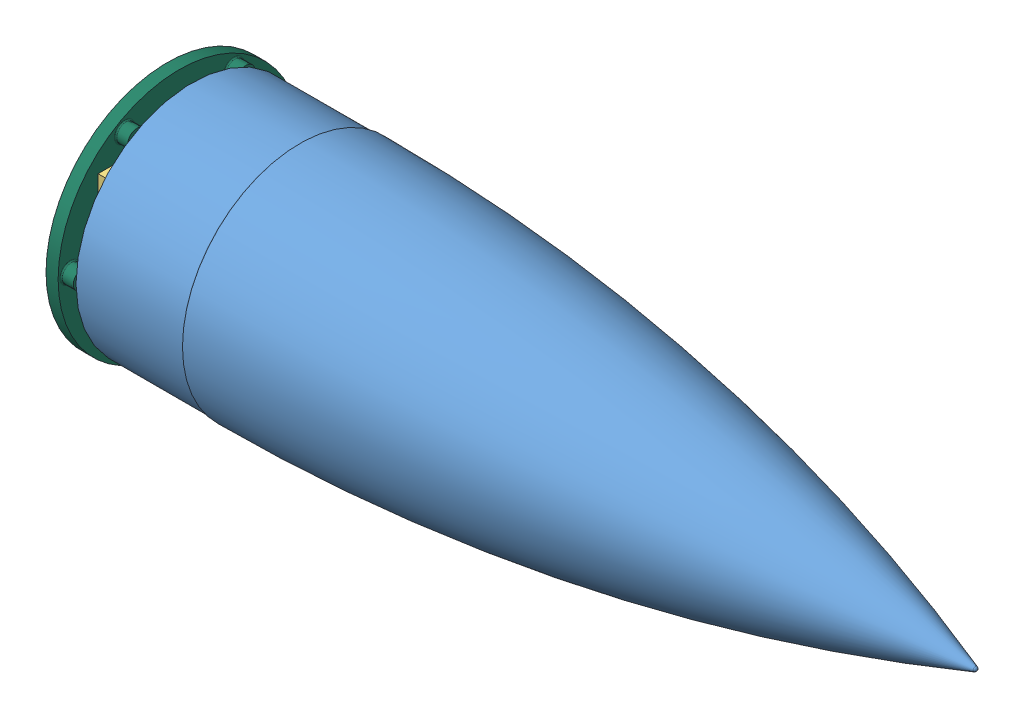
SolidWorks assembly nose_asm, configuration 預設. Lengths in mm.
Overall size (708.47 200 200).
227 component instances, 67 part files, 3 mates.
Components (placement in the parent):
- nosecone-1: nosecone [預設] at origin size (647.8 194 194)
- avionics_asm-1: avionics_asm [預設] at (-668.4373 0 0) size (460.03 200 200)
  - avionics_base_1-1: avionics_base_1 [預設] at (85 0 0) size (10 165 165)
  - avionics_reassemb-2: avionics_reassemb [Default] at (153.5 -32.5546 1.2351) x (1 0 0) z (0 -1 0) size (134.36 127 95)
    - PCB_board_box_reassemb-1: PCB_board_box_reassemb [Default] at (0 -1.2351 -1.0546) size (121.33 127 95)
      - PCB_board_box_buttom-1: PCB_board_box_buttom [Default] at origin size (115 105 1)
      - PCB_board_box_front-1: PCB_board_box_front [Default] at (0 53.5 -36.5) x (0 0 -1) z (0 -1 0) size (75 115 1)
      - PCB_board_box_back-1: PCB_board_box_back [Default] at (0 -53.5 -36.5) x (0 0 1) z (0 1 0) size (75 115 1)
      - PCB_board_box_right-1: PCB_board_box_right [Default] at (58.5 0 -36.5) x (0 0 1) z (-1 0 0) size (85 127 1)
      - PCB_board_box_top-1: PCB_board_box_top [Default] at (0 0 -74) x (0 -1 0) z (0 0 1) size (105 115 1)
      - PCB_board_box_left-1: PCB_board_box_left [Default] at (-57.5 0 -36.5) x (0 0 1) z (-1 0 0) size (85 127 1)
      - connector_1-1: connector_1 [Default] at (-32.5 49.6 2.1) x (1 0 0) z (0 0 -1) size (10 10 10)
      - connector_1-2: connector_1 [Default] at (57.5 58.5 -36.5) x (0 0 1) z (-1 0 0) size (10 10 10)
      - connector_1-3: connector_1 [Default] at (57.5 -58.5 -36.5) x (0 0 -1) z (-1 0 0) size (10 10 10)
      - connector_1-4: connector_1 [Default] at (32.5 -49.6 2.1) x (-1 0 0) z (0 0 -1) size (10 10 10)
      - connector_1-5: connector_1 [Default] at (-32.5 -49.6 2.1) x (-1 0 0) z (0 0 -1) size (10 10 10)
      - connector_1-6: connector_1 [Default] at (-57.5 48.5 6) x (0 1 0) z (1 0 0) size (10 10 10)
      - connector_1-7: connector_1 [Default] at (-57.5 -48.5 6) x (0 1 0) z (1 0 0) size (10 10 10)
      - connector_1-8: connector_1 [Default] at (-57.5 58.5 -56.5) x (0 0 -1) z (1 0 0) size (10 10 10)
      - connector_1-9: connector_1 [Default] at (-57.5 -58.5 -56.5) x (0 0 1) z (1 0 0) size (10 10 10)
      - connector_1-10: connector_1 [Default] at (52.5 0 -74) x (0 -1 0) z (0 0 -1) size (10 10 10)
      - connector_1-11: connector_1 [Default] at (52.5 -49.6 -75.1) size (10 10 10)
      - connector_1-12: connector_1 [Default] at (-52.5 -54.6 -70.1) x (-1 0 0) z (0 1 0) size (10 10 10)
      - connector_1-13: connector_1 [Default] at (-52.5 49.6 -75.1) x (-1 0 0) z (0 0 1) size (10 10 10)
      - connector_1-14: connector_1 [Default] at (32.5 49.6 2.1) x (1 0 0) z (0 0 -1) size (10 10 10)
      - connector_1-15: connector_1 [Default] at (52.5 49.6 -75.1) x (-1 0 0) z (0 0 1) size (10 10 10)
      - ISO 10642 - M3 x  8-1: ISO 10642 - M3 x  8 [Default] at (-52.5 48.6 -71.3293) x (0 0 -1) z (-1 0 0) size (8 6 6)
      - ISO 10642 - M3 x  8-2: ISO 10642 - M3 x  8 [Default] at (-52.5 50.8293 -69.1) x (0 1 0) z (-1 0 0) size (8 6 6)
      - ISO 10642 - M3 x  8-3: ISO 10642 - M3 x  8 [Default] at (-52.5 -48.6 -71.3293) x (0 0 -1) z (-1 0 0) size (8 6 6)
      - ISO 10642 - M3 x  8-4: ISO 10642 - M3 x  8 [Default] at (-52.5 -50.8293 -69.1) x (0 -1 0) z (-1 0 0) size (8 6 6)
      - ISO 10642 - M3 x  8-5: ISO 10642 - M3 x  8 [Default] at (52.5 -50.7586 -69.1) x (0 -1 0) z (-1 0 0) size (8 6 6)
      - ISO 10642 - M3 x  8-6: ISO 10642 - M3 x  8 [Default] at (52.5 -48.6 -71.2586) x (0 0 -1) z (-1 0 0) size (8 6 6)
      - ISO 10642 - M3 x  8-7: ISO 10642 - M3 x  8 [Default] at (32.5 -48.6 -1.7414) x (0 0 1) z (-1 0 0) size (8 6 6)
      - ISO 10642 - M3 x  8-8: ISO 10642 - M3 x  8 [Default] at (32.5 -50.7586 -3.9) x (0 -1 0) z (-1 0 0) size (8 6 6)
      - ISO 10642 - M3 x  8-9: ISO 10642 - M3 x  8 [Default] at (-32.5 -48.6 -1.7414) x (0 0 1) z (-1 0 0) size (8 6 6)
      - ISO 10642 - M3 x  8-10: ISO 10642 - M3 x  8 [Default] at (-32.5 -50.7586 -3.9) x (0 -1 0) z (-1 0 0) size (8 6 6)
      - ISO 10642 - M3 x  8-11: ISO 10642 - M3 x  8 [Default] at (32.5 48.6 -1.7414) x (0 0 1) z (-1 0 0) size (8 6 6)
      - ISO 10642 - M3 x  8-12: ISO 10642 - M3 x  8 [Default] at (32.5 50.7586 -3.9) x (0 1 0) z (-1 0 0) size (8 6 6)
      - ISO 10642 - M3 x  8-13: ISO 10642 - M3 x  8 [Default] at (-32.5 48.6 -1.6707) x (0 0 1) z (-1 0 0) size (8 6 6)
      - ISO 10642 - M3 x  8-14: ISO 10642 - M3 x  8 [Default] at (-32.5 50.7586 -3.9) x (0 1 0) z (-1 0 0) size (8 6 6)
      - ISO 10642 - M3 x  8-15: ISO 10642 - M3 x  8 [Default] at (52.5 48.6 -71.2586) x (0 0 -1) z (-1 0 0) size (8 6 6)
      - ISO 10642 - M3 x  8-16: ISO 10642 - M3 x  8 [Default] at (52.5 50.7586 -69.1) x (0 1 0) z (-1 0 0) size (8 6 6)
      - ISO 10642 - M3 x  8-17: ISO 10642 - M3 x  8 [Default] at (51.5 0 -76.7414) x (0 0 1) z (-1 0 0) size (8 6 6)
      - ISO 10642 - M3 x  8-18: ISO 10642 - M3 x  8 [Default] at (54.7586 0 -80) x (1 0 0) z (0 0 -1) size (8 6 6)
      - ISO 10642 - M3 x  8-19: ISO 10642 - M3 x  8 [Default] at (54.7586 -59.5 -36.5) x (1 0 0) z (0 0 -1) size (8 6 6)
      - ISO 10642 - M3 x  8-20: ISO 10642 - M3 x  8 [Default] at (51.5 -56.2414 -36.5) x (0 1 0) z (-1 0 0) size (8 6 6)
      - ISO 10642 - M3 x  8-21: ISO 10642 - M3 x  8 [Default] at (51.5 56.2414 -36.5) x (0 -1 0) z (-1 0 0) size (8 6 6)
      - ISO 10642 - M3 x  8-22: ISO 10642 - M3 x  8 [Default] at (54.8293 59.5 -36.5) x (1 0 0) z (0 0 -1) size (8 6 6)
      - ISO 10642 - M3 x  8-23: ISO 10642 - M3 x  8 [Default] at (-51.5 56.1707 -56.5) x (0 -1 0) z (-1 0 0) size (8 6 6)
      - ISO 10642 - M3 x  8-25: ISO 10642 - M3 x  8 [Default] at (-51.5 48.5 3.7414) x (0 0 -1) z (-1 0 0) size (8 6 6)
      - ISO 10642 - M3 x  8-28: ISO 10642 - M3 x  8 [Default] at (-51.5 -48.5 3.7414) x (0 0 -1) z (-1 0 0) size (8 6 6)
      - ISO 10642 - M3 x  8-30: ISO 10642 - M3 x  8 [Default] at (-51.5 -56.1707 -56.5) x (0 1 0) z (-1 0 0) size (8 6 6)
      - ISO 4032 - M3-1: ISO 4032 - M3 [Default] at (-52.5 48.6 -77.5) x (0 0 1) z (-1 0 0) size (2.4 6.35 5.5)
      - ISO 4032 - M3-2: ISO 4032 - M3 [Default] at (-52.5 54.6 -69.1) x (0 1 0) z (-1 0 0) size (2.4 6.35 5.5)
      - ISO 4032 - M3-3: ISO 4032 - M3 [Default] at (-51.5 52.5 -56.5) x (0 -1 0) z (-1 0 0) size (2.4 6.35 5.5)
      - ISO 4032 - M3-4: ISO 4032 - M3 [Default] at (-52.5 -48.6 -75.1) x (0 0 -1) z (-1 0 0) size (2.4 6.35 5.5)
      - ISO 4032 - M3-5: ISO 4032 - M3 [Default] at (-52.5 -54.6 -69.1) x (0 -1 0) z (-1 0 0) size (2.4 6.35 5.5)
      - ISO 4032 - M3-6: ISO 4032 - M3 [Default] at (-51.5 -52.5 -56.5) x (0 1 0) z (-1 0 0) size (2.4 6.35 5.5)
      - ISO 4032 - M3-7: ISO 4032 - M3 [Default] at (-51.5 -48.5 0) x (0 0 -1) z (-1 0 0) size (2.4 6.35 5.5)
      - ISO 4032 - M3-8: ISO 4032 - M3 [Default] at (-51.5 48.5 0) x (0 0 -1) z (-1 0 0) size (2.4 6.35 5.5)
      - ISO 4032 - M3-9: ISO 4032 - M3 [Default] at (-32.5 57 -3.9) x (0 -1 0) z (-1 0 0) size (2.4 6.35 5.5)
      - ISO 4032 - M3-10: ISO 4032 - M3 [Default] at (-32.5 48.6 4.5) x (0 0 -1) z (-1 0 0) size (2.4 6.35 5.5)
      - ISO 4032 - M3-11: ISO 4032 - M3 [Default] at (-32.5 -48.6 2.1) x (0 0 1) z (-1 0 0) size (2.4 6.35 5.5)
      - ISO 4032 - M3-12: ISO 4032 - M3 [Default] at (-32.5 -57 -3.9) x (0 1 0) z (-1 0 0) size (2.4 6.35 5.5)
      - ISO 4032 - M3-13: ISO 4032 - M3 [Default] at (52.5 -48.6 -75.1) x (0 0 -1) z (-1 0 0) size (2.4 6.35 5.5)
      - ISO 4032 - M3-14: ISO 4032 - M3 [Default] at (52.5 -54.6 -69.1) x (0 -1 0) z (-1 0 0) size (2.4 6.35 5.5)
      - ISO 4032 - M3-15: ISO 4032 - M3 [Default] at (52.5 48.6 -75.1) x (0 0 -1) z (-1 0 0) size (2.4 6.35 5.5)
      - ISO 4032 - M3-16: ISO 4032 - M3 [Default] at (52.5 54.6 -69.1) x (0 1 0) z (-1 0 0) size (2.4 6.35 5.5)
      - ISO 4032 - M3-17: ISO 4032 - M3 [Default] at (32.5 57 -3.9) x (0 -1 0) z (-1 0 0) size (2.4 6.35 5.5)
      - ISO 4032 - M3-18: ISO 4032 - M3 [Default] at (32.5 48.6 4.5) x (0 0 -1) z (-1 0 0) size (2.4 6.35 5.5)
      - ISO 4032 - M3-19: ISO 4032 - M3 [Default] at (32.5 -48.6 4.5) x (0 0 -1) z (-1 0 0) size (2.4 6.35 5.5)
      - ISO 4032 - M3-20: ISO 4032 - M3 [Default] at (32.5 -57 -3.9) x (0 1 0) z (-1 0 0) size (2.4 6.35 5.5)
      - ISO 4032 - M3-21: ISO 4032 - M3 [Default] at (51.5 -52.5 -36.5) x (0 1 0) z (-1 0 0) size (2.4 6.35 5.5)
      - ISO 4032 - M3-22: ISO 4032 - M3 [Default] at (51.5 52.5 -36.5) x (0 -1 0) z (-1 0 0) size (2.4 6.35 5.5)
      - ISO 4032 - M3-23: ISO 4032 - M3 [Default] at (58.5 0 -80) size (2.4 6.35 5.5)
      - ISO 4032 - M3-24: ISO 4032 - M3 [Default] at (58.5 -59.5 -36.5) size (2.4 6.35 5.5)
      - ISO 4032 - M3-25: ISO 4032 - M3 [Default] at (58.5 59.5 -36.5) size (2.4 6.35 5.5)
    - PCB-1: PCB [Default] at (47.58 -45.05 -4.8556) x (0 1 0) z (0 0 -1) size (90.17 95.89 17.8)
    - copper_pillar_M3_L15-1: copper_pillar_M3_L15 [Default] at (42.5 -36.16 0) x (1 0 0) z (0 1 0) size (5.77 16 5)
    - copper_pillar_M3_L15-2: copper_pillar_M3_L15 [Default] at (-43.225 40.04 0) x (1 0 0) z (0 1 0) size (5.77 16 5)
    - copper_pillar_M3_L15-3: copper_pillar_M3_L15 [Default] at (42.5 37.5 0) x (1 0 0) z (0 1 0) size (5.77 16 5)
    - copper_pillar_M3_L15-4: copper_pillar_M3_L15 [Default] at (-43.225 -39.97 0) x (1 0 0) z (0 1 0) size (5.77 16 5)
    - washerM3x0.5h-1: washerM3x0.5h [Default] at (-43.225 -39.97 -4.5) size (6.7 6.7 0.5)
    - washerM3x0.5h-2: washerM3x0.5h [Default] at (42.5 -36.16 -4.5) size (6.7 6.7 0.5)
    - washerM3x0.5h-3: washerM3x0.5h [Default] at (-43.225 40.04 -4) x (1 0 0) z (0 0 -1) size (6.7 6.7 0.5)
    - washerM3x0.5h-4: washerM3x0.5h [Default] at (42.5 37.5 -4) x (1 0 0) z (0 0 -1) size (6.7 6.7 0.5)
    - copper_pillar_M3_L15_1-1: copper_pillar_M3_L15_1 [Default] at (42.5 -36.16 -5.3556) x (1 0 0) z (0 1 0) size (5.77 26 5)
    - copper_pillar_M3_L15_1-2: copper_pillar_M3_L15_1 [Default] at (42.5 37.5 -5.3556) x (1 0 0) z (0 1 0) size (5.77 26 5)
    - copper_pillar_M3_L15_1-3: copper_pillar_M3_L15_1 [Default] at (-43.225 40.04 -5.3556) x (1 0 0) z (0 1 0) size (5.77 26 5)
    - copper_pillar_M3_L15_1-4: copper_pillar_M3_L15_1 [Default] at (-43.225 -39.97 -5.3556) x (1 0 0) z (0 1 0) size (5.77 26 5)
    - washerM3x0.5h-5: washerM3x0.5h [Default] at (-43.225 40.04 -5.3556) size (6.7 6.7 0.5)
    - washerM3x0.5h-6: washerM3x0.5h [Default] at (-43.225 -39.97 -4.8556) x (1 0 0) z (0 0 -1) size (6.7 6.7 0.5)
    - washerM3x0.5h-7: washerM3x0.5h [Default] at (42.5 -36.16 -4.8556) x (1 0 0) z (0 0 -1) size (6.7 6.7 0.5)
    - washerM3x0.5h-8: washerM3x0.5h [Default] at (42.5 37.5 -4.8556) x (1 0 0) z (0 0 -1) size (6.7 6.7 0.5)
    - washerM3x0.5h-9: washerM3x0.5h [Default] at (-43.225 40.04 -19.3556) x (1 0 0) z (0 0 -1) size (6.7 6.7 0.5)
    - washerM3x0.5h-10: washerM3x0.5h [Default] at (-43.225 -39.97 -19.3556) x (1 0 0) z (0 0 -1) size (6.7 6.7 0.5)
    - washerM3x0.5h-11: washerM3x0.5h [Default] at (42.5 -36.16 -19.3556) x (1 0 0) z (0 0 -1) size (6.7 6.7 0.5)
    - washerM3x0.5h-12: washerM3x0.5h [Default] at (42.5 37.5 -19.3556) x (1 0 0) z (0 0 -1) size (6.7 6.7 0.5)
    - STM32 Communication Board ver1.0-1: STM32 Communication Board ver1.0 [Default] at (42.5 -36.16 -21.3601) x (0 1 0) z (0 0 -1) size (90.17 95.89 10)
    - washerM3x0.5h-13: washerM3x0.5h [Default] at (42.5 -36.16 -21.3601) x (1 0 0) z (0 0 -1) size (6.7 6.7 0.5)
    - washerM3x0.5h-14: washerM3x0.5h [Default] at (-43.225 -39.97 -21.3601) x (1 0 0) z (0 0 -1) size (6.7 6.7 0.5)
    - washerM3x0.5h-15: washerM3x0.5h [Default] at (42.5 37.5 -21.3601) x (1 0 0) z (0 0 -1) size (6.7 6.7 0.5)
    - washerM3x0.5h-16: washerM3x0.5h [Default] at (-43.225 40.04 -21.3601) x (1 0 0) z (0 0 -1) size (6.7 6.7 0.5)
    - copper_pillar_M3_L25_1-1: copper_pillar_M3_L25_1 [Default] at (-43.225 -39.97 -21.8601) x (1 0 0) z (0 1 0) size (5.77 37 5)
    - copper_pillar_M3_L25_1-2: copper_pillar_M3_L25_1 [Default] at (42.5 -36.16 -21.8601) x (1 0 0) z (0 1 0) size (5.77 37 5)
    - copper_pillar_M3_L25_1-3: copper_pillar_M3_L25_1 [Default] at (42.5 37.5 -21.8601) x (1 0 0) z (0 1 0) size (5.77 37 5)
    - copper_pillar_M3_L25_1-4: copper_pillar_M3_L25_1 [Default] at (-43.225 40.04 -21.8601) x (1 0 0) z (0 1 0) size (5.77 37 5)
    - washerM3x0.5h-17: washerM3x0.5h [Default] at (42.5 37.5 -47.3601) size (6.7 6.7 0.5)
    - washerM3x0.5h-18: washerM3x0.5h [Default] at (-43.225 40.04 -46.8601) x (1 0 0) z (0 0 -1) size (6.7 6.7 0.5)
    - washerM3x0.5h-19: washerM3x0.5h [Default] at (42.5 -36.16 -47.3601) size (6.7 6.7 0.5)
    - washerM3x0.5h-20: washerM3x0.5h [Default] at (-43.225 -39.97 -47.3601) size (6.7 6.7 0.5)
    - empty_board-1: empty_board [Default] at (0.08 0.12 -47.3601) x (0 1 0) z (-1 0 0) size (90 1.45 95)
    - MTi-1_v3-1: MTi-1_v3 [Default] at (-8.5645 -18.7527 -51.9664) x (0 1 0) z (0 0 -1) size (53.34 66.07 22.31)
      - Board_1v2(2)^MTi-1-SoB_v2-1: Board_1v2(2)^MTi-1-SoB_v2 [Default] at origin size (12.15 12.15 1.56)
        - Open CASCADE STEP translator 6.8 2.1.1^Board_1v2(2)_MTi-1-SoB_v2-1: Open CASCADE STEP translator 6.8 2.1.1^Board_1v2(2)_MTi-1-SoB_v2 [Default] at (0 0 -1.5563) size (12.15 12.15 1.56)
          - Open CASCADE STEP translator 6.8 2.1.1.1^Open CASCADE STEP translator_ 6.8 2.1.1_Board_1v2(2)_MTi-1-SoB_v2-1: Open CASCADE STEP translator 6.8 2.1.1.1^Open CASCADE STEP translator_ 6.8 2.1.1_Board_1v2(2)_MTi-1-SoB_v2 [Default] at origin size (12.15 12.15 1.56)
      - U200_1v2(2)^MTi-1-SoB_v2-1: U200_1v2(2)^MTi-1-SoB_v2 [Default] at origin size (3.1 3.3 0.6)
        - 7460079024(2)^U200_1v2(2)_MTi-1-SoB_v2-1: 7460079024(2)^U200_1v2(2)_MTi-1-SoB_v2 [Default] at (5.6 3.4 0) size (3.1 3.3 0.6)
          - Extruded(2)^7460079024(2)_U200_1v2(2)_MTi-1-SoB_v2-1: Extruded(2)^7460079024(2)_U200_1v2(2)_MTi-1-SoB_v2 [Default] at origin size (3.1 3.3 0.6)
      - C200_1v2(2)^MTi-1-SoB_v2-1: C200_1v2(2)^MTi-1-SoB_v2 [Default] at origin size (1.05 0.55 0.55)
        - Cap_0402(2)^C200_1v2(2)_MTi-1-SoB_v2-1: Cap_0402(2)^C200_1v2(2)_MTi-1-SoB_v2 [Default] at (5.3999 6.9749 0.26) x (-1 0 0) z (0 0 1) size (1.05 0.55 0.55)
      - C201_1v2(2)^MTi-1-SoB_v2-1: C201_1v2(2)^MTi-1-SoB_v2 [Default] at origin size (1.05 0.55 0.55)
        - Cap_0402(2)^C201_1v2(2)_MTi-1-SoB_v2-1: Cap_0402(2)^C201_1v2(2)_MTi-1-SoB_v2 [Default] at (6.7999 1.375 0.26) x (-1 0 0) z (0 0 1) size (1.05 0.55 0.55)
      - C204_1v2(2)^MTi-1-SoB_v2-1: C204_1v2(2)^MTi-1-SoB_v2 [Default] at origin size (1.05 0.55 0.55)
        - Cap_0402(2)^C204_1v2(2)_MTi-1-SoB_v2-1: Cap_0402(2)^C204_1v2(2)_MTi-1-SoB_v2 [Default] at (8.1999 3.0749 0.26) x (-1 0 0) z (0 0 1) size (1.05 0.55 0.55)
      - C205_1v2(2)^MTi-1-SoB_v2-1: C205_1v2(2)^MTi-1-SoB_v2 [Default] at origin size (1.05 0.55 0.55)
        - Cap_0402(2)^C205_1v2(2)_MTi-1-SoB_v2-1: Cap_0402(2)^C205_1v2(2)_MTi-1-SoB_v2 [Default] at (4.2001 0.8251 0.26) x (1 0 0) z (0 0 1) size (1.05 0.55 0.55)
      - C206_1v2(2)^MTi-1-SoB_v2-1: C206_1v2(2)^MTi-1-SoB_v2 [Default] at origin size (0.55 1.05 0.55)
        - Cap_0402(2)^C206_1v2(2)_MTi-1-SoB_v2-1: Cap_0402(2)^C206_1v2(2)_MTi-1-SoB_v2 [Default] at (3.1251 4.5999 0.26) x (0 -1 0) z (0 0 1) size (1.05 0.55 0.55)
      - C207_1v2(2)^MTi-1-SoB_v2-1: C207_1v2(2)^MTi-1-SoB_v2 [Default] at origin size (1.05 0.55 0.55)
        - Cap_0402(2)^C207_1v2(2)_MTi-1-SoB_v2-1: Cap_0402(2)^C207_1v2(2)_MTi-1-SoB_v2 [Default] at (7.3001 5.4251 0.26) x (1 0 0) z (0 0 1) size (1.05 0.55 0.55)
      - C208_1v2(2)^MTi-1-SoB_v2-1: C208_1v2(2)^MTi-1-SoB_v2 [Default] at origin size (0.55 1.05 0.55)
        - Cap_0402(2)^C208_1v2(2)_MTi-1-SoB_v2-1: Cap_0402(2)^C208_1v2(2)_MTi-1-SoB_v2 [Default] at (3.1251 2.5999 0.26) x (0 -1 0) z (0 0 1) size (1.05 0.55 0.55)
      - C209_1v2(2)^MTi-1-SoB_v2-1: C209_1v2(2)^MTi-1-SoB_v2 [Default] at origin size (1.05 0.55 0.55)
        - Cap_0402(2)^C209_1v2(2)_MTi-1-SoB_v2-1: Cap_0402(2)^C209_1v2(2)_MTi-1-SoB_v2 [Default] at (8.6001 1.4251 0.26) x (1 0 0) z (0 0 1) size (1.05 0.55 0.55)
      - C300_1v2(2)^MTi-1-SoB_v2-1: C300_1v2(2)^MTi-1-SoB_v2 [Default] at origin size (0.55 1.05 0.55)
        - Cap_0402(2)^C300_1v2(2)_MTi-1-SoB_v2-1: Cap_0402(2)^C300_1v2(2)_MTi-1-SoB_v2 [Default] at (10.425 8.2999 0.26) x (0 -1 0) z (0 0 1) size (1.05 0.55 0.55)
      - C301_1v2(2)^MTi-1-SoB_v2-1: C301_1v2(2)^MTi-1-SoB_v2 [Default] at origin size (1.05 0.55 0.55)
        - Cap_0402(2)^C301_1v2(2)_MTi-1-SoB_v2-1: Cap_0402(2)^C301_1v2(2)_MTi-1-SoB_v2 [Default] at (3.4001 10.375 0.26) x (1 0 0) z (0 0 1) size (1.05 0.55 0.55)
      - C302_1v2(2)^MTi-1-SoB_v2-1: C302_1v2(2)^MTi-1-SoB_v2 [Default] at origin size (1.05 0.55 0.55)
        - Cap_0402(2)^C302_1v2(2)_MTi-1-SoB_v2-1: Cap_0402(2)^C302_1v2(2)_MTi-1-SoB_v2 [Default] at (5.5999 8.0749 0.26) x (-1 0 0) z (0 0 1) size (1.05 0.55 0.55)
      - C303_1v2(2)^MTi-1-SoB_v2-1: C303_1v2(2)^MTi-1-SoB_v2 [Default] at origin size (1.05 0.55 0.55)
        - Cap_0402(2)^C303_1v2(2)_MTi-1-SoB_v2-1: Cap_0402(2)^C303_1v2(2)_MTi-1-SoB_v2 [Default] at (7.2999 6.9749 0.26) x (-1 0 0) z (0 0 1) size (1.05 0.55 0.55)
      - C305_1v2(2)^MTi-1-SoB_v2-1: C305_1v2(2)^MTi-1-SoB_v2 [Default] at origin size (0.55 1.05 0.55)
        - Cap_0402(2)^C305_1v2(2)_MTi-1-SoB_v2-1: Cap_0402(2)^C305_1v2(2)_MTi-1-SoB_v2 [Default] at (6.4749 9.3001 0.26) x (0 1 0) z (0 0 1) size (1.05 0.55 0.55)
      - C304_1v2(2)^MTi-1-SoB_v2-1: C304_1v2(2)^MTi-1-SoB_v2 [Default] at origin size (0.55 1.05 0.55)
        - Cap_0402(2)^C304_1v2(2)_MTi-1-SoB_v2-1: Cap_0402(2)^C304_1v2(2)_MTi-1-SoB_v2 [Default] at (5.4749 9.3001 0.26) x (0 1 0) z (0 0 1) size (1.05 0.55 0.55)
      - R200_1v2(2)^MTi-1-SoB_v2-1: R200_1v2(2)^MTi-1-SoB_v2 [Default] at origin size (1 0.5 0.35)
        - RES0402(2)^R200_1v2(2)_MTi-1-SoB_v2-1: RES0402(2)^R200_1v2(2)_MTi-1-SoB_v2 [Default] at (-16.787 18.2331 0) x (-1 0 0) z (0 1 0) size (1 0.35 0.5)
      - R300_1v2(2)^MTi-1-SoB_v2-1: R300_1v2(2)^MTi-1-SoB_v2 [Default] at origin size (0.5 1 0.35)
        - RES0402(2)^R300_1v2(2)_MTi-1-SoB_v2-1: RES0402(2)^R300_1v2(2)_MTi-1-SoB_v2 [Default] at (13.6331 30.587 0) x (0 1 0) z (1 0 0) size (1 0.35 0.5)
      - R301_1v2(2)^MTi-1-SoB_v2-1: R301_1v2(2)^MTi-1-SoB_v2 [Default] at origin size (0.5 1 0.35)
        - RES0402(2)^R301_1v2(2)_MTi-1-SoB_v2-1: RES0402(2)^R301_1v2(2)_MTi-1-SoB_v2 [Default] at (21.9331 28.487 0) x (0 1 0) z (1 0 0) size (1 0.35 0.5)
      - S300_1v2(2)^MTi-1-SoB_v2-1: S300_1v2(2)^MTi-1-SoB_v2 [Default] at origin size (3 3 1)
        - 6752205952(2)^S300_1v2(2)_MTi-1-SoB_v2-1: 6752205952(2)^S300_1v2(2)_MTi-1-SoB_v2 [Default] at (8.4999 8.8999 0) size (3 3 1)
          - Extruded-1(2)^6752205952(2)_S300_1v2(2)_MTi-1-SoB_v2-1: Extruded-1(2)^6752205952(2)_S300_1v2(2)_MTi-1-SoB_v2 [Default] at origin size (3 3 1)
      - S301_1v2(2)^MTi-1-SoB_v2-1: S301_1v2(2)^MTi-1-SoB_v2 [Default] at origin size (2.5 3 0.86)
        - User_Library-LGA-14_2_5x3(2)^S301_1v2(2)_MTi-1-SoB_v2-1: User_Library-LGA-14_2_5x3(2)^S301_1v2(2)_MTi-1-SoB_v2 [Default] at (3.1 8.3 0.85) x (0 -1 0) z (1 0 0) size (3 0.86 2.5)
      - R302_1v2(2)^MTi-1-SoB_v2-1: R302_1v2(2)^MTi-1-SoB_v2 [Default] at origin size (0.5 1 0.35)
        - RES0402(2)^R302_1v2(2)_MTi-1-SoB_v2-1: RES0402(2)^R302_1v2(2)_MTi-1-SoB_v2 [Default] at (22.9331 28.487 0) x (0 1 0) z (1 0 0) size (1 0.35 0.5)
      - C202_1v2(2)^MTi-1-SoB_v2-1: C202_1v2(2)^MTi-1-SoB_v2 [Default] at origin size (1.05 0.55 0.55)
        - Cap_0402(2)^C202_1v2(2)_MTi-1-SoB_v2-1: Cap_0402(2)^C202_1v2(2)_MTi-1-SoB_v2 [Default] at (8.2001 4.4251 0.26) x (1 0 0) z (0 0 1) size (1.05 0.55 0.55)
      - C203_1v2(2)^MTi-1-SoB_v2-1: C203_1v2(2)^MTi-1-SoB_v2 [Default] at origin size (1.05 0.55 0.55)
        - Cap_0402(2)^C203_1v2(2)_MTi-1-SoB_v2-1: Cap_0402(2)^C203_1v2(2)_MTi-1-SoB_v2 [Default] at (8.2001 3.4251 0.26) x (1 0 0) z (0 0 1) size (1.05 0.55 0.55)
      - Y200_1v2(2)^MTi-1-SoB_v2-1: Y200_1v2(2)^MTi-1-SoB_v2 [Default] at origin size (1.61 2.01 0.31)
        - User_Library-Crystal_(NDK)_2.0x1.6(2)^Y200_1v2(2)_MTi-1-SoB_v2-1: User_Library-Crystal_(NDK)_2.0x1.6(2)^Y200_1v2(2)_MTi-1-SoB_v2 [Default] at (10.2 4.0001 0) x (0 -1 0) z (-1 0 0) size (2.01 0.31 1.61)
      - R303_1v2(2)^MTi-1-SoB_v2-1: R303_1v2(2)^MTi-1-SoB_v2 [Default] at origin size (0.5 1 0.35)
        - RES0402(2)^R303_1v2(2)_MTi-1-SoB_v2-1: RES0402(2)^R303_1v2(2)_MTi-1-SoB_v2 [Default] at (-1.8331 -11.987 0) x (0 -1 0) z (-1 0 0) size (1 0.35 0.5)
      - Mti-7 development board-1: Mti-7 development board [Default] at (6.7227 17.82 -3.1563) x (1 0 0) z (0 -1 0) size (53.34 18.51 57.52)
      - GNSS_board-1: GNSS_board [Default] at (6.6927 40.5245 6.9537) size (25 37 6)
    - ISO 4032 - M3-1: ISO 4032 - M3 [Default] at (-43.225 -39.97 -48.8101) x (0 0 -1) z (1 0 0) size (2.4 6.35 5.5)
    - ISO 4032 - M3-2: ISO 4032 - M3 [Default] at (-43.225 40.04 -48.8101) x (0 0 -1) z (1 0 0) size (2.4 6.35 5.5)
    - ISO 4032 - M3-3: ISO 4032 - M3 [Default] at (42.5 -36.16 -50.4101) x (0 0 -1) z (1 0 0) size (2.4 6.35 5.5)
    - ISO 4032 - M3-4: ISO 4032 - M3 [Default] at (42.5 37.5 -48.8101) x (0 0 -1) z (1 0 0) size (2.4 6.35 5.5)
    - CUI_DEVICES_CFM-4010V-070-273-1: CUI_DEVICES_CFM-4010V-070-273 [Default] at (58.5 -34.5 -18) x (0 -1 0) z (0 0 1) size (0.06 0.01 0.07)
    - screw- M3 x  15-1: screw- M3 x  15 [預設] at (-54.7586 58.2649 -57.5546) x (-1 0 0) z (0 -0.924225 -0.381849) size (16.7 6 6)
    - ISO 4032 - M3-5: ISO 4032 - M3 [Default] at (-60.9 58.2649 -57.5546) x (1 0 0) z (0 1 0) size (2.4 6.35 5.5)
    - ISO 4032 - M3-6: ISO 4032 - M3 [Default] at (-60.9 47.2649 5.9454) x (1 0 0) z (0 1 0) size (2.4 6.35 5.5)
    - screw- M3 x  15-2: screw- M3 x  15 [預設] at (-54.8293 47.2649 5.9454) x (-1 0 0) z (0 -0.924225 -0.381849) size (16.7 6 6)
    - screw- M3 x  15-3: screw- M3 x  15 [預設] at (-54.8293 -49.7351 5.9454) x (-1 0 0) z (0 -0.924225 -0.381849) size (16.7 6 6)
    - ISO 4032 - M3-10: ISO 4032 - M3 [Default] at (-60.9 -49.7351 5.9454) x (1 0 0) z (0 1 0) size (2.4 6.35 5.5)
    - screw- M3 x  15-4: screw- M3 x  15 [預設] at (-54.7586 -60.7351 -57.5546) x (-1 0 0) z (0 -0.924225 -0.381849) size (16.7 6 6)
    - ISO 4032 - M3-11: ISO 4032 - M3 [Default] at (-60.9 -60.7351 -57.5546) x (1 0 0) z (0 1 0) size (2.4 6.35 5.5)
  - ISO 4032 - M3-1: ISO 4032 - M3 [Default] at (82.6 -38.5 -48.5) size (2.4 6.35 5.5)
  - ISO 4032 - M3-3: ISO 4032 - M3 [Default] at (82.6 -38.5 48.5) size (2.4 6.35 5.5)
  - ISO 4032 - M3-4: ISO 4032 - M3 [Default] at (82.6 25 59.5) size (2.4 6.35 5.5)
  - ISO 4032 - M3-5: ISO 4032 - M3 [Default] at (82.6 25 -59.5) size (2.4 6.35 5.5)
  - avionics_base_2-1: avionics_base_2 [預設] at (220 0 0) size (10 165 165)
  - avionics_base_3-1: avionics_base_3 [預設] at (310 0 0) size (10 165 165)
  - avionics_base_4-1: avionics_base_4 [預設] at origin size (20 200 200)
  - eyesbolt_M6L20-1: eyesbolt_M6L20 [預設] at (-15 0 0) x (0 0 -1) z (0 1 0) size (27.58 50.03 13.77)
  - screw_M10L15-1: screw_M10L15 [預設] at (-15 70 0) x (0 -0.95145 0.307802) z (0 0.307802 0.95145) size (8 350 8)
  - screw_M10L15-2: screw_M10L15 [預設] at (335 -70 0) x (0 0.103686 0.99461) z (0 -0.99461 0.103686) size (8 350 8)
  - flangenut_M10P1_5-29: flangenut_M10P1_5 [預設] at (-15 -70 0) x (0 0 1) z (-1 0 0) size (22 22 15)
  - flangenut_M10P1_5-25: flangenut_M10P1_5 [預設] at (25 -70 0) x (0 -0.728748 0.684782) z (1 0 0) size (22 22 15)
  - flangenut_M10P1_5-26: flangenut_M10P1_5 [預設] at (-15 70 0) x (0 0 1) z (-1 0 0) size (22 22 15)
  - flangenut_M10P1_5-20: flangenut_M10P1_5 [預設] at (25 70 0) x (0 -0.924225 -0.381849) z (1 0 0) size (22 22 15)
  - flangenut_M10P1_5-23: flangenut_M10P1_5 [預設] at (70 70 0) x (0 -0.934057 0.357123) z (-1 0 0) size (22 22 15)
  - flangenut_M10P1_5-24: flangenut_M10P1_5 [預設] at (70 -70 0) x (0 -0.928922 0.370275) z (-1 0 0) size (22 22 15)
  - flangenut_M10P1_5-28: flangenut_M10P1_5 [預設] at (110 70 0) x (0 -0.607422 0.79438) z (1 0 0) size (22 22 15)
  - flangenut_M10P1_5-17: flangenut_M10P1_5 [預設] at (110 -70 0) x (0 -0.696926 0.717143) z (1 0 0) size (22 22 15)
  - flangenut_M10P1_5-27: flangenut_M10P1_5 [預設] at (205 70 0) x (0 -0.928922 0.370275) z (-1 0 0) size (22 22 15)
  - flangenut_M10P1_5-21: flangenut_M10P1_5 [預設] at (205 -70 0) x (0 -0.928922 0.370275) z (-1 0 0) size (22 22 15)
  - flangenut_M10P1_5-19: flangenut_M10P1_5 [預設] at (245 70 0) x (0 -0.696926 0.717143) z (1 0 0) size (22 22 15)
  - flangenut_M10P1_5-22: flangenut_M10P1_5 [預設] at (245 -70 0) x (0 -0.569431 0.822039) z (1 0 0) size (22 22 15)
  - PA_base_adaptor-1: PA_base_adaptor [預設] at (230 9 -9) x (0 1 0) z (1 0 0) size (72 64 7)
  - flangenut_M10P1_5-18: flangenut_M10P1_5 [預設] at (295 70 0) x (0 -0.928922 0.370275) z (-1 0 0) size (22 22 15)
  - flangenut_M10P1_5-30: flangenut_M10P1_5 [預設] at (335 70 0) x (0 -0.696926 0.717143) z (1 0 0) size (22 22 15)
  - flangenut_M10P1_5-32: flangenut_M10P1_5 [預設] at (295 -70 0) x (0 -0.991803 0.127778) z (-1 0 0) size (22 22 15)
  - flangenut_M10P1_5-31: flangenut_M10P1_5 [預設] at (335 -70 0) x (0 -0.496815 0.867857) z (1 0 0) size (22 22 15)
  - PA_AMP_ERAM_1W-1: PA_AMP_ERAM_1W [預設] at (255 10.5 -9) x (0 0 1) z (0 -1 0) size (103 24 71)
  - battery_box_7V4-2: battery_box_7V4 [預設] at (32.7044 98 49.9748) x (0 0 -1) z (0 -1 0) size (60 35 83)
    - battery_box_7V4-1: battery_box_7V4 [預設] at (4.9748 -22.7044 78) size (60 35 78)
    - battery_cap_7V4-1: battery_cap_7V4 [預設] at (4.9748 -5.2044 117) size (60 35 5)
    - battery7_4Vmodel-1: battery7_4Vmodel [預設] at (4.9748 -2.7044 74.5) x (0 0 1) z (0 -1 0) size (68 38 20)
  - battery_box_14V8-2: battery_box_14V8 [預設] at (50.9203 98 -9.3105) x (0 0 -1) z (0 -1 0) size (60 57 83)
    - battery_box_14V8-1: battery_box_14V8 [預設] at (17.6895 -40.9203 78) size (60 57 78)
    - battery_cap_14V8-1: battery_cap_14V8 [預設] at (17.6895 -12.4203 117) size (60 57 5)
    - battery14_8Vmodel-1: battery14_8Vmodel [預設] at (17.6895 -8.9203 78) x (0 0 1) z (0 -1 0) size (75 38 44)
  - GPSR_antenna_asm-1: GPSR_antenna_asm [預設] at (331.5055 78 -20.8772) x (0 0 -1) z (0 -1 0) size (60 24 60)
    - GPSR_antenna_base-1: GPSR_antenna_base [預設] at (6.1228 -11.5055 60) size (60 7 60)
    - GPSR_antenna_cap-1: GPSR_antenna_cap [預設] at (6.1228 12.4945 60) x (-1 0 0) z (0 0 1) size (60 17 60)
    - GPSR_antenna-1: GPSR_antenna [預設] at (6.1228 -4.5055 60) x (0 0 -1) z (1 0 0) size (56.1 13.5 52.2)
  - stick_antenna_asm-1: stick_antenna_asm [預設] at (452.4231 121.0365 -52.8915) x (0 -1 0) z (0 0 1) size (50 100 48)
    - stick_antenna_cap-1: stick_antenna_cap [預設] at (112.0365 -132.4231 79.8915) size (50 100 24)
    - stick_antenna_cap-2: stick_antenna_cap [預設] at (112.0365 -132.4231 79.8915) x (-1 0 0) z (0 0 -1) size (50 100 24)
  - air_tube_adaptor1-1: air_tube_adaptor1 [預設] at (230 -45.0213 17) x (0 -0.002129 -0.999998) z (0 -0.999998 0.002129) size (40 25 20)
Mates (geometry in assembly coordinates):
- 同軸心1: concentric aligned: cylinder of nosecone-1 through (-711 0 0) axis (-1 0 0) radius 95.88; cylinder of avionics_asm-1/avionics_base_1-1 through (-573.4373 0 0) axis (-1 0 0) radius 82.5
- 重合/共線/共點3: coincident aligned: plane of avionics_asm-1 through (-668.4373 0 0) normal (0 1 0)
- 相切1: tangent: torus of nosecone-1; circle of avionics_asm-1/avionics_base_3-1
